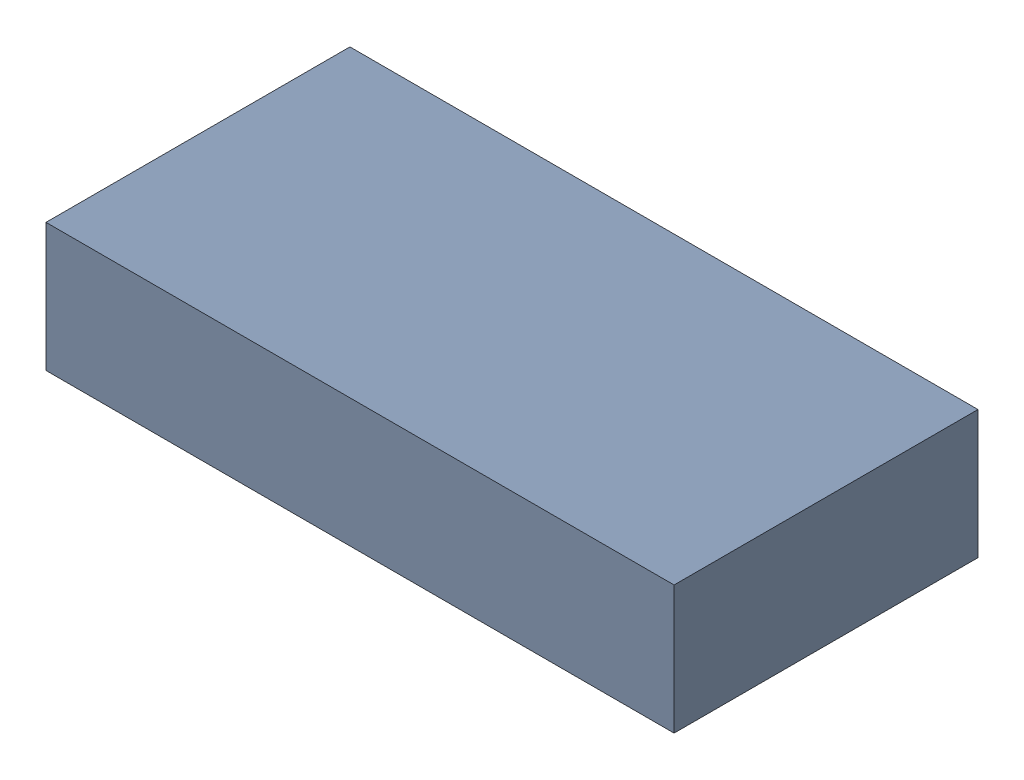
SolidWorks assembly 2CellBattery, configuration Default. Lengths in mm.
Overall size (70.87 14.48 34.29).
3 component instances, 2 part files, 7 mates.
Components (placement in the parent):
- Battery-1: Battery [Default] at (-10.6627 -1.4184 6.5902) size (70.87 14.48 34.29)
- WireNub-1: WireNub [Default] at (-32.4977 13.0596 28.8096) x (-1 0 0) z (0 0.994935 -0.100524) (suppressed, hidden)
- WireNub-2: WireNub [Default] at (-32.5005 12.9746 -6.7504) x (-0.997758 0.066927 0) z (0.015289 0.227936 -0.973556) (suppressed, hidden)
Mates (geometry in assembly coordinates):
- Tangent6: tangent anti-aligned: plane of Battery-1 through (-33.7677 13.0596 28.1746) normal (0 0 1); cylinder of WireNub-1 through (-33.7677 13.0596 28.8096) axis (1 0 0) radius 0.635
- Coincident8: coincident: line of Battery-1 through (-33.7677 13.0596 28.1746) axis (0 -1 0); plane of WireNub-1 through (-33.7677 13.0596 28.8096) normal (-1 0 0)
- Coincident10: coincident: point of Battery-1; circle of WireNub-1
- Lock1: lock: unknown of Battery-1; unknown of WireNub-1
- Coincident13: coincident: point of Battery-1; circle of WireNub-2
- Tangent8: tangent: plane of Battery-1 through (-33.7677 13.0596 -6.1154) normal (0 0 -1); cylinder of WireNub-2 through (-33.7677 13.0596 -6.7504) axis (0.997758 -0.066927 0) radius 0.635
- Lock2: lock: unknown of Battery-1; unknown of WireNub-2
